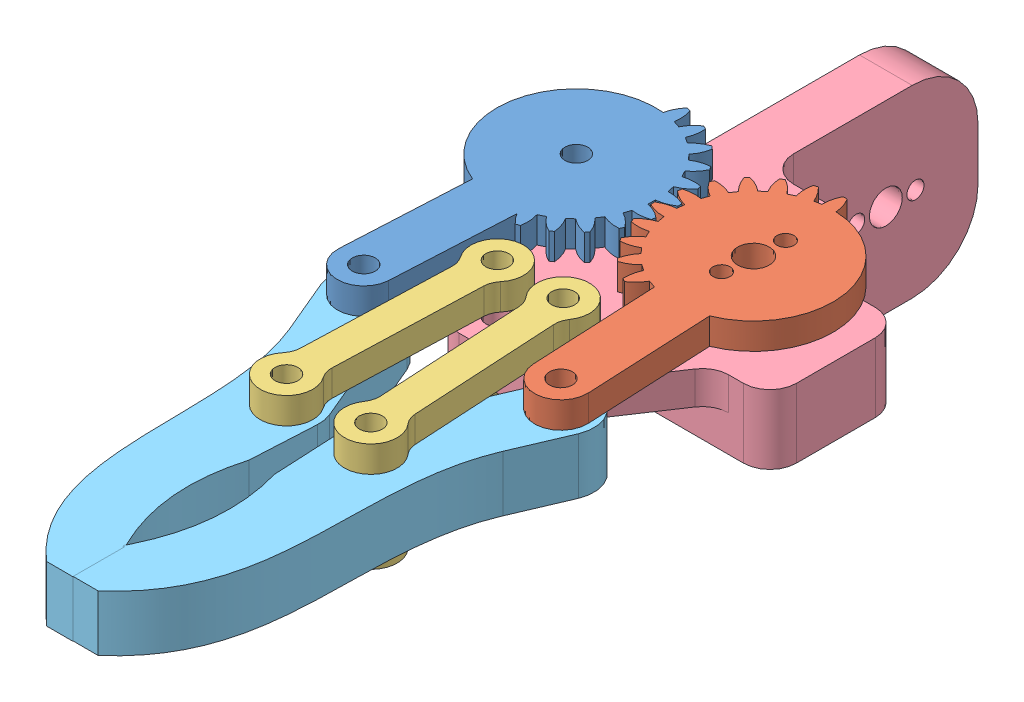
SolidWorks assembly Gripper Assembly, configuration Default. Lengths in mm.
Overall size (65.56 35.5 144.98).
9 component instances, 5 part files, 21 mates.
Components (placement in the parent):
- gear1-1: gear1 [Default] at (-17.5467 12.6028 65.1565) x (-0.051418 0 0.998677) z (-0.998677 0 -0.051418) size (49.29 4 26.63)
- gear2-1: gear2 [Default] at (10.7105 12.6028 44.992) x (0.082871 0 -0.99656) z (0.99656 0 0.082871) size (49.02 4 26.63)
- grip link 1-1: grip link 1 [Default] at (-10.0646 0.1028 106.0462) x (0.033468 0 -0.99944) z (0.99944 0 0.033468) size (39 4 8)
- Gripper base-1: Gripper base [Default] at (-22.027 4.1028 80.0636) size (44.4 28 77)
- grip link 1-2: grip link 1 [Default] at (2.7155 0.1028 106.0146) x (-0.056211 0 -0.998419) z (0.998419 0 -0.056211) size (39 4 8)
- Gripper 1-1: Gripper 1 [Default] at (8.7088 4.1028 79.2175) x (0 1 0) z (0.392312 0 -0.919832) size (8.5 22.22 65.31)
- Gripper 1-2: Gripper 1 [Default] at (-15.9423 12.6028 79.2236) x (0 -1 0) z (-0.388345 0 -0.921514) size (8.5 22.22 65.31)
- grip link 1-3: grip link 1 [Default] at (2.7155 12.6028 106.0146) x (-0.056211 0 -0.998419) z (0.998419 0 -0.056211) size (39 4 8)
- grip link 1-4: grip link 1 [Default] at (-10.0646 16.6028 106.0462) x (0.033468 0 -0.99944) z (-0.99944 0 -0.033468) size (39 4 8)
Mates (geometry in assembly coordinates):
- Concentric1: concentric aligned: cylinder of gear1-1 through (-17.027 16.6028 55.0636) axis (0 -1 0) radius 1.75; cylinder of Gripper base-1 through (-17.027 9.1028 55.0636) axis (0 -1 0) radius 1.75
- Concentric2: concentric anti-aligned: cylinder of Gripper base-1 through (9.873 4.1028 55.0636) axis (0 -1 0) radius 5.4; cylinder of gear2-1 through (9.873 12.6018 55.0636) axis (0 1 0) radius 2.4
- Coincident1: coincident aligned: plane of gear1-1 through (-18.6081 16.6028 85.7729) normal (0 1 0); plane of gear2-1 through (12.4212 16.6028 24.4193) normal (0 1 0)
- Concentric4: concentric aligned: cylinder of grip link 1-1 through (-9.027 4.1028 75.0636) axis (0 -1 0) radius 1.75; cylinder of Gripper base-1 through (-9.027 9.1028 75.0636) axis (0 -1 0) radius 1.75
- Concentric51: concentric aligned: cylinder of Gripper base-1 through (0.973 9.1028 75.0636) axis (0 -1 0) radius 1.75; cylinder of grip link 1-2 through (0.973 4.1028 75.0636) axis (0 -1 0) radius 1.75
- Concentric6: concentric anti-aligned: cylinder of gear2-1 through (11.3464 12.6028 85.7783) axis (0 1 0) radius 1.75; cylinder of Gripper 1-1 through (11.3464 12.6028 85.7783) axis (0 -1 0) radius 1.75
- Concentric7: concentric aligned: cylinder of grip link 1-2 through (2.7155 4.1028 106.0146) axis (0 -1 0) radius 1.75; cylinder of Gripper 1-1 through (2.7155 12.6028 106.0146) axis (0 -1 0) radius 1.75
- Concentric8: concentric anti-aligned: cylinder of gear1-1 through (-18.6081 16.6028 85.7729) axis (0 -1 0) radius 1.75; cylinder of Gripper 1-2 through (-18.6081 4.1028 85.7729) axis (0 1 0) radius 1.75
- Concentric9: concentric anti-aligned: cylinder of grip link 1-1 through (-10.0646 4.1028 106.0462) axis (0 -1 0) radius 1.75; cylinder of Gripper 1-2 through (-10.0646 4.1028 106.0462) axis (0 1 0) radius 1.75
- Coincident2: coincident anti-aligned: plane of Gripper base-1 through (-22.027 4.1028 80.0636) normal (0 -1 0); plane of grip link 1-2 through (2.7155 4.1028 106.0146) normal (0 1 0)
- Coincident3: coincident anti-aligned: plane of grip link 1-1 through (-10.0646 4.1028 106.0462) normal (0 1 0); plane of Gripper base-1 through (-22.027 4.1028 80.0636) normal (0 -1 0)
- Coincident4: coincident anti-aligned: plane of gear2-1 through (12.4212 12.6028 24.4193) normal (0 -1 0); plane of Gripper 1-1 through (8.7088 12.6028 79.2175) normal (0 1 0)
- Coincident5: coincident anti-aligned: plane of gear1-1 through (-18.6081 12.6028 85.7729) normal (0 -1 0); plane of Gripper 1-2 through (-15.9423 12.6028 79.2236) normal (0 1 0)
- Distance1: distance = 3.5 mm anti-aligned: plane of Gripper base-1 through (-22.027 9.1028 80.0636) normal (0 1 0); plane of gear2-1 through (12.4212 12.6028 24.4193) normal (0 -1 0)
- GearMate1: gear = 3 : 3 mm: circle of gear1-1; cylinder of gear2-1 through (9.873 12.6018 55.0636) axis (0 1 0) radius 2.4
- Concentric11: concentric aligned: cylinder of Gripper 1-1 through (2.7155 12.6028 106.0146) axis (0 -1 0) radius 1.75; cylinder of grip link 1-3 through (2.7155 16.6028 106.0146) axis (0 -1 0) radius 1.75
- Coincident8: coincident anti-aligned: plane of Gripper 1-1 through (8.7088 12.6028 79.2175) normal (0 1 0); plane of grip link 1-3 through (2.7155 12.6028 106.0146) normal (0 -1 0)
- Concentric12: concentric aligned: cylinder of Gripper base-1 through (0.973 9.1028 75.0636) axis (0 -1 0) radius 1.75; cylinder of grip link 1-3 through (0.973 16.6028 75.0636) axis (0 -1 0) radius 1.75
- Concentric131: concentric aligned: cylinder of Gripper 1-2 through (-10.0646 4.1028 106.0462) axis (0 1 0) radius 1.75; cylinder of grip link 1-4 through (-10.0646 12.6028 106.0462) axis (0 1 0) radius 1.75
- Concentric14: concentric anti-aligned: cylinder of Gripper base-1 through (-9.027 9.1028 75.0636) axis (0 -1 0) radius 1.75; cylinder of grip link 1-4 through (-9.027 12.6028 75.0636) axis (0 1 0) radius 1.75
- Coincident9: coincident aligned: plane of grip link 1-3 through (2.7155 16.6028 106.0146) normal (0 1 0); plane of grip link 1-4 through (-10.0646 16.6028 106.0462) normal (0 1 0)
